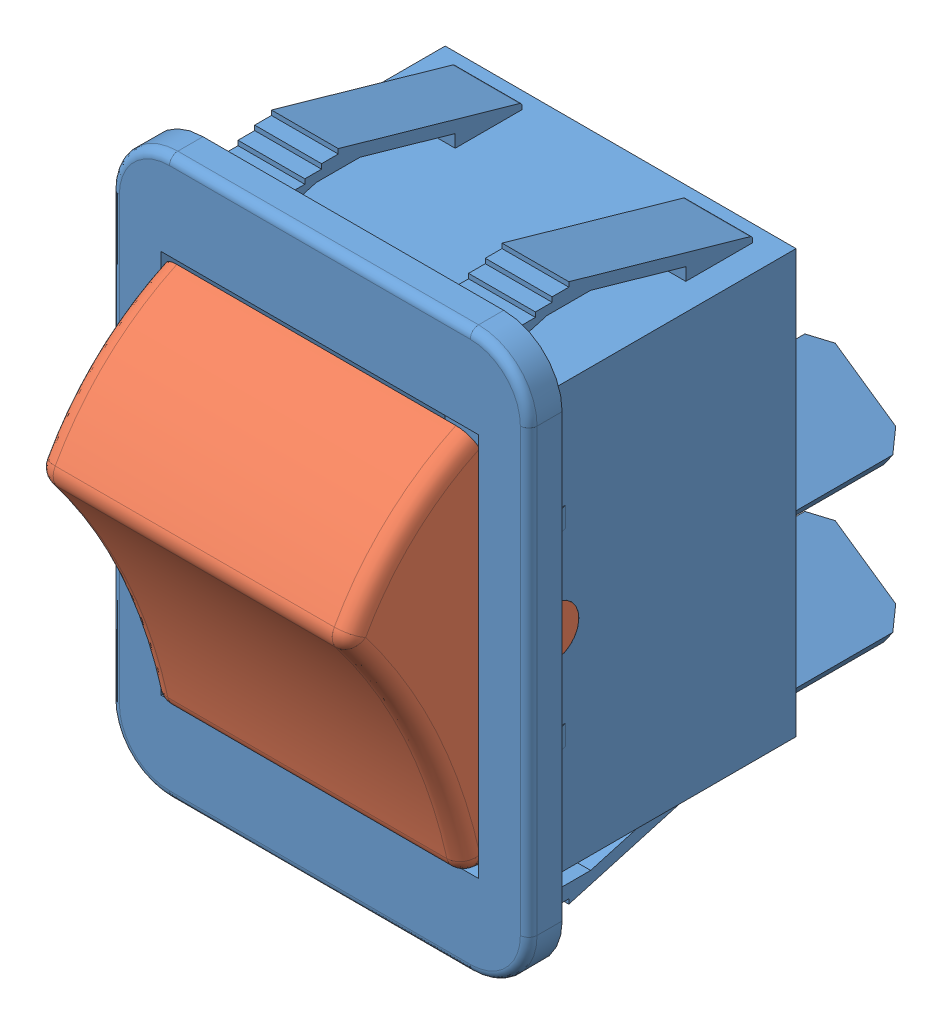
SolidWorks assembly Bulgin-C1350XB, configuration Default. Lengths in mm.
Overall size (25 33.4 36.47).
2 component instances, 2 part files, 3 mates.
Components (placement in the parent):
- Switch-body^Bulgin-C1350XB-1: Switch-body^Bulgin-C1350XB [Default] at origin size (25 33.4 27.3) (virtual)
- Rocker^Bulgin-C1350XB-1: Rocker^Bulgin-C1350XB [Default] at (0 0.6339 -2.8595) x (1 0 0) z (0 -0.906308 -0.422618) size (21 9.88 24) (virtual)
Mates (geometry in assembly coordinates):
- Concentric1: concentric anti-aligned: cylinder of Switch-body^Bulgin-C1350XB-1 through (-12.5 0 -1.5) axis (1 0 0) radius 1.5; cylinder of Rocker^Bulgin-C1350XB-1 through (10.5 0 -1.5) axis (-1 0 0) radius 1.5
- Coincident1: coincident aligned: circle of Switch-body^Bulgin-C1350XB-1; circle of Rocker^Bulgin-C1350XB-1
- LimitAngle1: limit planar angle = 0.436332 rad: plane of assembly through (0 0 0) normal (0 0 1); plane of assembly; plane of Rocker^Bulgin-C1350XB-1 through (0 0.6339 -2.8595) normal (0 -0.422618 0.906308)
